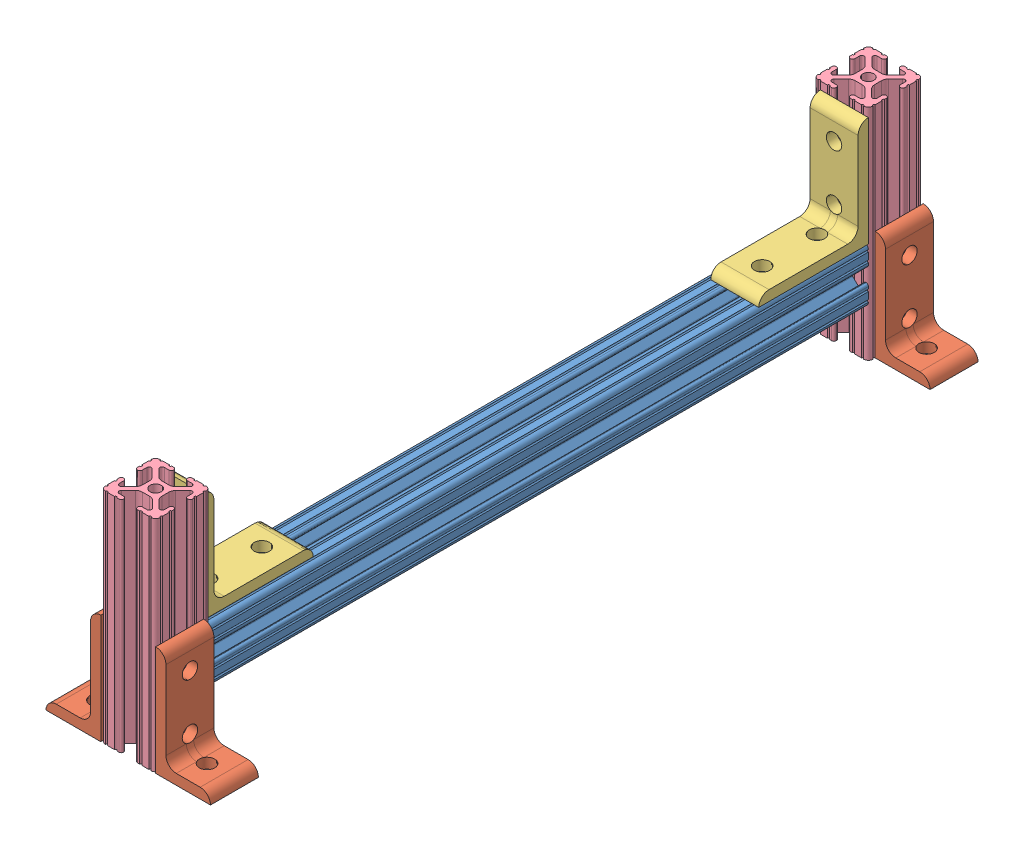
SolidWorks assembly DP ion pump support assembly 2, configuration Default. Lengths in mm.
Overall size (76.2 101.6 355.6).
9 component instances, 4 part files, 24 mates.
Components (placement in the parent):
- 8020-1010 - 12 inches-1: 8020-1010 - 12 inches [Default] at (-100.411 -80.4882 107.668) size (25.4 25.4 304.8)
- 8020-4176-1: 8020-4176 [Default] at (-109.6086 -92.4314 -222.532) x (0 0 1) z (0 1 0) size (22.23 25.4 50.8)
- 8020-4115-1: 8020-4115 [Default] at (-109.936 -89.6859 -174.5312) size (22.23 50.8 50.8)
- 8020-1010 - 4 inches-1: 8020-1010 - 4 inches [Default] at (-100.411 -13.4322 -209.832) x (0 0 1) z (0 1 0) size (25.4 25.4 101.6)
- 8020-4115-2: 8020-4115 [Default] at (-90.886 -89.6859 85.0671) x (-1 0 0) z (0 0 -1) size (22.23 50.8 50.8)
- 8020-1010 - 4 inches-2: 8020-1010 - 4 inches [Default] at (-100.411 -13.4322 120.368) x (1 0 0) z (0 1 0) size (25.4 25.4 101.6)
- 8020-4176-2: 8020-4176 [Default] at (-91.2133 -92.4314 -200.307) x (0 0 -1) z (0 1 0) size (22.23 25.4 50.8)
- 8020-4176-3: 8020-4176 [Default] at (-91.2133 -92.4314 133.068) x (0 0 -1) z (0 1 0) size (22.23 25.4 50.8)
- 8020-4176-4: 8020-4176 [Default] at (-109.6086 -92.4314 110.843) x (0 0 1) z (0 1 0) size (22.23 25.4 50.8)
Mates (geometry in assembly coordinates):
- Coincident1: coincident aligned: plane of 8020-1010 - 12 inches-1 through (-102.1202 -88.159 -197.132) normal (0 0 -1); plane of 8020-4115-1 through (-87.711 -16.9882 -197.132) normal (0 0 -1)
- Coincident2: coincident anti-aligned: plane of 8020-1010 - 12 inches-1 through (-109.9614 -67.7882 -197.132) normal (0 1 0); plane of 8020-4115-1 through (-87.711 -67.7882 -146.332) normal (0 -1 0)
- Coincident3: coincident aligned: plane of 8020-1010 - 12 inches-1 through (-87.711 -74.1551 -197.132) normal (1 0 0); plane of 8020-4115-1 through (-87.711 -67.7882 -151.1072) normal (1 0 0)
- Coincident4: coincident anti-aligned: plane of 8020-4115-1 through (-87.711 -16.9882 -197.132) normal (0 0 -1); plane of 8020-1010 - 4 inches-1 through (-94.0778 -109.9522 -197.132) normal (0 0 1)
- Coincident5: coincident aligned: plane of 8020-4115-1 through (-87.711 -67.7882 -151.1072) normal (1 0 0); plane of 8020-1010 - 4 inches-1 through (-87.711 -109.9522 -200.2816) normal (1 0 0)
- Distance1: distance = 21.844 mm aligned: plane of 8020-1010 - 4 inches-1 through (-108.0818 -115.0322 -211.5413) normal (0 -1 0); plane of 8020-1010 - 12 inches-1 through (-94.0778 -93.1882 -197.132) normal (0 -1 0)
- Coincident7: coincident anti-aligned: plane of 8020-4176-1 through (-87.711 -59.1522 -200.307) normal (-1 0 0); plane of 8020-1010 - 4 inches-1 through (-87.711 -109.9522 -200.2816) normal (1 0 0)
- Coincident8: coincident aligned: plane of 8020-4176-1 through (-36.911 -109.9522 -200.307) normal (0 -1 0); plane of 8020-1010 - 4 inches-1 through (-108.0818 -109.9522 -211.5413) normal (0 -1 0)
- Coincident9: coincident aligned: plane of 8020-4176-1 through (-87.711 -63.9274 -222.532) normal (0 0 -1); plane of 8020-1010 - 4 inches-1 through (-94.0778 -109.9522 -222.532) normal (0 0 -1)
- Coincident10: coincident aligned: plane of 8020-1010 - 12 inches-1 through (-102.1202 -88.159 107.668) normal (0 0 1); plane of 8020-4115-2 through (-113.111 -16.9882 107.668) normal (0 0 1)
- Coincident11: coincident anti-aligned: plane of 8020-1010 - 12 inches-1 through (-109.9614 -67.7882 -197.132) normal (0 1 0); plane of 8020-4115-2 through (-113.111 -67.7882 56.868) normal (0 -1 0)
- Coincident12: coincident aligned: plane of 8020-1010 - 12 inches-1 through (-113.111 -74.1551 -197.132) normal (-1 0 0); plane of 8020-4115-2 through (-113.111 -67.7882 61.6432) normal (-1 0 0)
- Coincident13: coincident anti-aligned: plane of 8020-4115-2 through (-113.111 -16.9882 107.668) normal (0 0 1); plane of 8020-1010 - 4 inches-2 through (-90.8606 -115.0322 107.668) normal (0 0 -1)
- Coincident14: coincident aligned: plane of 8020-4115-2 through (-113.111 -67.7882 61.6432) normal (-1 0 0); plane of 8020-1010 - 4 inches-2 through (-113.111 -115.0322 114.0349) normal (-1 0 0)
- Distance2: distance = 21.844 mm aligned: plane of 8020-1010 - 12 inches-1 through (-106.7441 -93.1882 -197.132) normal (0 -1 0); plane of 8020-1010 - 4 inches-2 through (-102.1202 -115.0322 128.0388) normal (0 -1 0)
- Coincident16: coincident aligned: plane of 8020-1010 - 4 inches-1 through (-108.0818 -109.9522 -211.5413) normal (0 -1 0); plane of 8020-4176-2 through (-163.911 -109.9522 -222.532) normal (0 -1 0)
- Coincident17: coincident anti-aligned: plane of 8020-1010 - 4 inches-1 through (-113.111 -109.9522 -216.1651) normal (-1 0 0); plane of 8020-4176-2 through (-113.111 -59.1522 -222.532) normal (1 0 0)
- Coincident18: coincident aligned: plane of 8020-4176-1 through (-87.711 -63.9274 -222.532) normal (0 0 -1); plane of 8020-4176-2 through (-113.111 -63.9274 -222.532) normal (0 0 -1)
- Coincident19: coincident anti-aligned: plane of 8020-1010 - 4 inches-2 through (-113.111 -115.0322 129.9184) normal (-1 0 0); plane of 8020-4176-3 through (-113.111 -64.2322 110.843) normal (1 0 0)
- Coincident20: coincident aligned: plane of 8020-1010 - 4 inches-2 through (-106.7441 -115.0322 133.068) normal (0 0 1); plane of 8020-4176-3 through (-113.111 -69.0074 133.068) normal (0 0 1)
- Coincident21: coincident aligned: plane of 8020-1010 - 4 inches-2 through (-102.1202 -115.0322 128.0388) normal (0 -1 0); plane of 8020-4176-3 through (-163.911 -115.0322 110.843) normal (0 -1 0)
- Coincident22: coincident anti-aligned: plane of 8020-1010 - 4 inches-2 through (-87.711 -115.0322 114.0349) normal (1 0 0); plane of 8020-4176-4 through (-87.711 -64.2322 133.068) normal (-1 0 0)
- Coincident23: coincident aligned: plane of 8020-1010 - 4 inches-2 through (-94.0778 -115.0322 133.068) normal (0 0 1); plane of 8020-4176-4 through (-87.711 -69.0074 133.068) normal (0 0 1)
- Coincident24: coincident aligned: plane of 8020-4176-3 through (-163.911 -115.0322 110.843) normal (0 -1 0); plane of 8020-4176-4 through (-36.911 -115.0322 133.068) normal (0 -1 0)
